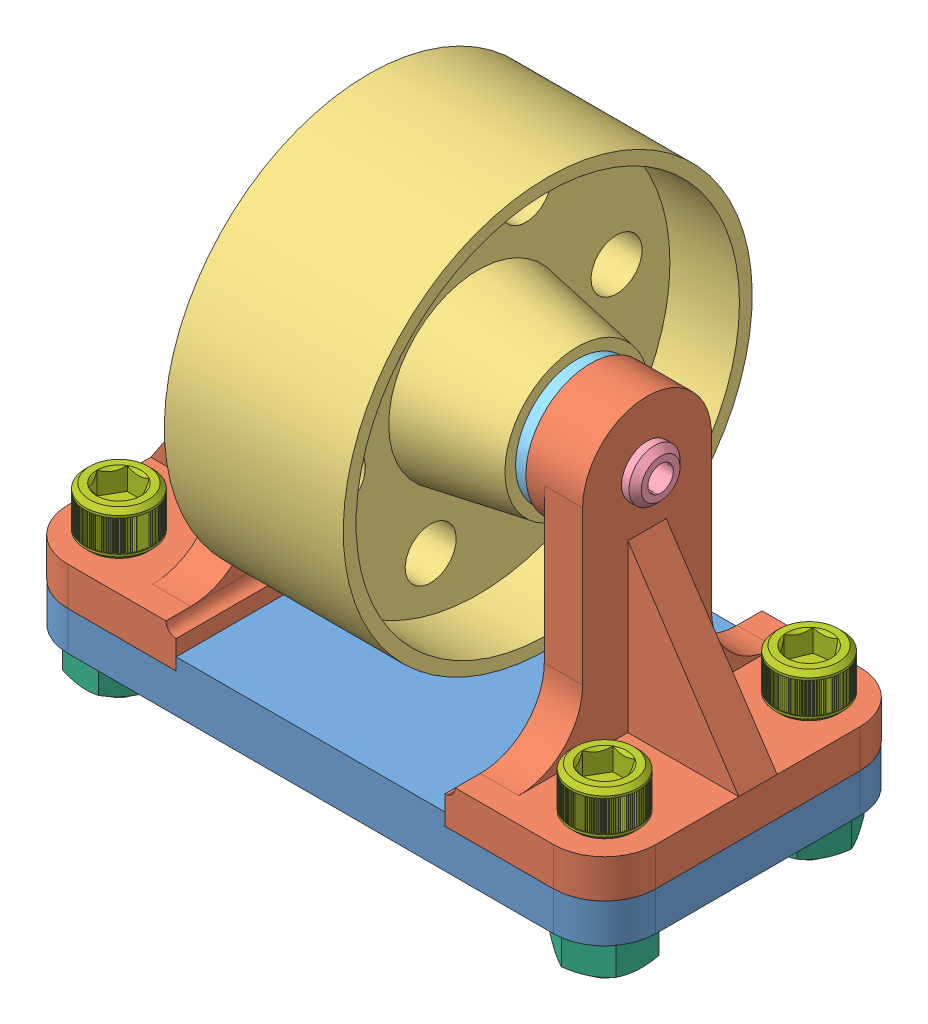
SolidWorks assembly DRFT21-21 EXP, configuration Default. Lengths in mm.
Overall size (147.18 157.92 143.19).
15 component instances, 7 part files, 29 mates.
Components (placement in the parent):
- DRFT21-21A-1: DRFT21-21A [Default] at origin size (146.05 12.7 76.2)
- DRFT21-21B-1: DRFT21-21B [Default] at (-35.941 19.177 0) x (0 0 1) z (-1 0 0) size (76.2 79.5 41.66)
- DRFT21-21B-2: DRFT21-21B [Default] at (35.941 19.177 0) x (0 0 -1) z (1 0 0) size (76.2 79.5 41.66)
- DRFT21-21C-1: DRFT21-21C [Default] at (-1.2954 64.9493 9.6957) x (0 -0.763439 -0.64588) z (0 -0.64588 0.763439) size (101.6 58.72 101.6)
- DRFT21-21D-1: DRFT21-21D [Default] at (-52.7558 73.152 0) x (0 -0.999962 -0.008726) z (-1 0 0) size (19.05 19.05 101.75)
- DRFT21-21E-1: DRFT21-21E [Default] at (12.5476 73.152 0) x (0 -0.74503 -0.66703) z (1 0 0) size (30.49 30.49 18.82)
- DRFT21-21E-2: DRFT21-21E [Default] at (-16.6116 73.152 0) x (0 -0.999361 0.035735) z (-1 0 0) size (30.49 30.49 18.82)
- 95479A215_Medium-Strength Steel Hex Nut-1: 95479A215_Medium-Strength Steel Hex Nut [95479A215] at (60.325 -4.7625 -25.4) x (-0.046715 0 -0.998908) z (0 -1 0) size (17.46 20.16 10.53)
- 91251A002_Black-Oxide Alloy Steel Socket Head Screw-1: 91251A002_Black-Oxide Alloy Steel Socket Head Screw [91251A002] at (60.325 8.8582 -25.4) x (-0.925789 0 -0.37804) z (0 1 0) size (16.67 16.67 44.02)
- 95479A215_Medium-Strength Steel Hex Nut-2: 95479A215_Medium-Strength Steel Hex Nut [95479A215] at (60.325 -4.7625 25.4) x (0.553832 0 -0.832628) z (0 1 0) size (17.46 20.16 10.53)
- 91251A002_Black-Oxide Alloy Steel Socket Head Screw-2: 91251A002_Black-Oxide Alloy Steel Socket Head Screw [91251A002] at (60.325 8.8582 25.4) x (0.869876 0 -0.49327) z (0 1 0) size (16.67 16.67 44.02)
- 91251A002_Black-Oxide Alloy Steel Socket Head Screw-4: 91251A002_Black-Oxide Alloy Steel Socket Head Screw [91251A002] at (-60.325 8.8582 25.4) x (0.869876 0 -0.49327) z (0 1 0) size (16.67 16.67 44.02)
- 95479A215_Medium-Strength Steel Hex Nut-4: 95479A215_Medium-Strength Steel Hex Nut [95479A215] at (-60.325 -4.7625 25.4) x (0.81025 0 0.586084) z (0 1 0) size (17.46 20.16 10.53)
- 91251A002_Black-Oxide Alloy Steel Socket Head Screw-5: 91251A002_Black-Oxide Alloy Steel Socket Head Screw [91251A002] at (-60.325 8.8582 -25.4) x (0.869876 0 -0.49327) z (0 1 0) size (16.67 16.67 44.02)
- 95479A215_Medium-Strength Steel Hex Nut-5: 95479A215_Medium-Strength Steel Hex Nut [95479A215] at (-60.325 -4.7625 -25.4) x (0.597669 0 0.801743) z (0 1 0) size (17.46 20.16 10.53)
Mates (geometry in assembly coordinates):
- Coincident1: coincident anti-aligned: plane of DRFT21-21A-1 through (0 9.652 0) normal (0 1 0); plane of DRFT21-21B-2 through (73.025 9.652 -38.1) normal (0 -1 0)
- Coincident2: coincident aligned: circle of DRFT21-21A-1; circle of DRFT21-21B-2
- Coincident3: coincident aligned: circle of DRFT21-21A-1; circle of DRFT21-21B-2
- Coincident6: coincident anti-aligned: plane of DRFT21-21A-1 through (-33.401 12.7 -38.1) normal (-1 0 0); plane of DRFT21-21B-1 through (-33.401 9.652 38.1) normal (1 0 0)
- Coincident7: coincident aligned: circle of DRFT21-21A-1; circle of DRFT21-21B-1
- Concentric1: concentric anti-aligned: cylinder of DRFT21-21B-2 through (60.325 19.177 -25.4) axis (0 1 0) radius 6.35; circle of 91251A002_Black-Oxide Alloy Steel Socket Head Screw-1
- Concentric2: concentric anti-aligned: circle of DRFT21-21A-1; circle of 95479A215_Medium-Strength Steel Hex Nut-1
- Coincident9: coincident anti-aligned: plane of DRFT21-21A-1 through (0 0 0) normal (0 -1 0); plane of 95479A215_Medium-Strength Steel Hex Nut-1 through (65.7684 0 -16.9138) normal (0 1 0)
- Coincident10: coincident anti-aligned: plane of DRFT21-21B-2 through (35.941 19.177 -38.1) normal (0 1 0); plane of 91251A002_Black-Oxide Alloy Steel Socket Head Screw-1 through (57.5944 19.177 -18.7129) normal (0 -1 0)
- Concentric3: concentric anti-aligned: circle of DRFT21-21B-2; circle of 91251A002_Black-Oxide Alloy Steel Socket Head Screw-2
- Coincident11: coincident anti-aligned: plane of DRFT21-21B-2 through (35.941 19.177 -38.1) normal (0 1 0); plane of 91251A002_Black-Oxide Alloy Steel Socket Head Screw-2 through (56.762 19.177 19.1168) normal (0 -1 0)
- Concentric4: concentric aligned: circle of DRFT21-21A-1; circle of 95479A215_Medium-Strength Steel Hex Nut-2
- Coincident14: coincident anti-aligned: plane of DRFT21-21A-1 through (0 0 0) normal (0 -1 0); plane of 95479A215_Medium-Strength Steel Hex Nut-2 through (51.2921 0 29.878) normal (0 1 0)
- Concentric5: concentric anti-aligned: cylinder of DRFT21-21D-1 through (-52.7558 73.152 0) axis (-1 0 0) radius 6.35; cylinder of DRFT21-21E-1 through (31.369 73.152 0) axis (1 0 0) radius 9.525
- Concentric6: concentric aligned: cylinder of DRFT21-21D-1 through (-52.7558 73.152 0) axis (-1 0 0) radius 6.35; cylinder of DRFT21-21E-2 through (-35.433 73.152 0) axis (-1 0 0) radius 9.525
- Coincident16: coincident aligned: circle of DRFT21-21D-1; circle of DRFT21-21E-2
- Coincident17: coincident anti-aligned: circle of DRFT21-21D-1; circle of DRFT21-21E-1
- Concentric7: concentric anti-aligned: cylinder of DRFT21-21C-1 through (28.067 73.152 0) axis (1 0 0) radius 12.7; cylinder of DRFT21-21D-1 through (-52.7558 73.152 0) axis (-1 0 0) radius 9.525
- Coincident18: coincident anti-aligned: plane of DRFT21-21C-1 through (28.067 61.5917 13.6645) normal (1 0 0); plane of DRFT21-21E-1 through (28.067 83.3204 -11.3574) normal (-1 0 0)
- Concentric8: concentric anti-aligned: cylinder of DRFT21-21B-2 through (45.466 73.152 0) axis (1 0 0) radius 6.35; cylinder of DRFT21-21D-1 through (-52.7558 73.152 0) axis (-1 0 0) radius 6.35
- Coincident19: coincident anti-aligned: plane of DRFT21-21B-2 through (31.369 73.152 0) normal (-1 0 0); plane of DRFT21-21E-1 through (31.369 73.152 0) normal (1 0 0)
- Concentric9: concentric anti-aligned: circle of DRFT21-21B-1; circle of 91251A002_Black-Oxide Alloy Steel Socket Head Screw-4
- Coincident20: coincident anti-aligned: plane of DRFT21-21B-1 through (-35.941 19.177 38.1) normal (0 1 0); plane of 91251A002_Black-Oxide Alloy Steel Socket Head Screw-4 through (-63.888 19.177 19.1168) normal (0 -1 0)
- Concentric10: concentric anti-aligned: circle of DRFT21-21B-1; circle of 91251A002_Black-Oxide Alloy Steel Socket Head Screw-5
- Coincident21: coincident anti-aligned: plane of DRFT21-21B-1 through (-35.941 19.177 38.1) normal (0 1 0); plane of 91251A002_Black-Oxide Alloy Steel Socket Head Screw-5 through (-63.888 19.177 -31.6832) normal (0 -1 0)
- Concentric11: concentric aligned: circle of DRFT21-21A-1; circle of 95479A215_Medium-Strength Steel Hex Nut-4
- Coincident22: coincident anti-aligned: plane of DRFT21-21A-1 through (0 0 0) normal (0 -1 0); plane of 95479A215_Medium-Strength Steel Hex Nut-4 through (-64.4451 0 16.1983) normal (0 1 0)
- Concentric12: concentric aligned: circle of DRFT21-21A-1; circle of 95479A215_Medium-Strength Steel Hex Nut-5
- Coincident23: coincident anti-aligned: plane of DRFT21-21A-1 through (0 0 0) normal (0 -1 0); plane of 95479A215_Medium-Strength Steel Hex Nut-5 through (-61.5018 0 -35.4131) normal (0 1 0)
